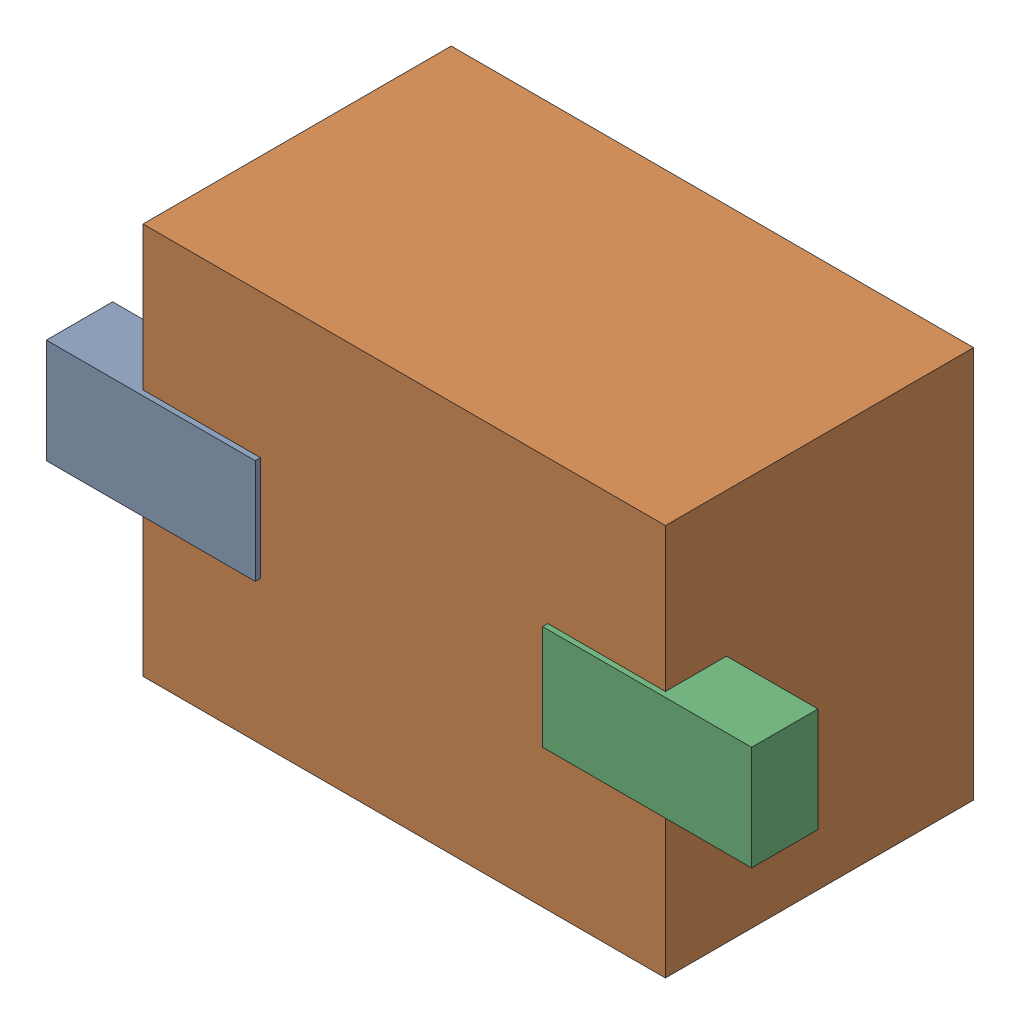
SolidWorks assembly D4, configuration Default. Lengths in mm.
Overall size (2.7 1.5 1.2).
6 component instances, 2 part files, 0 mates.
Components (placement in the parent):
- 710424080_6-1: 710424080_6 [Default] at (9.75 32.7 -0.6655) size (0.8 0.4 0.25)
  - Extruded (18)-1: Extruded (18) [Default] at origin size (0.8 0.4 0.25)
- 710423952_3-1: 710423952_3 [Default] at (10.7 32.7 -1.6115) size (2 1.5 1.18)
  - Extruded (19)-1: Extruded (19) [Default] at origin size (2 1.5 1.18)
- 710424080_7-1: 710424080_7 [Default] at (11.65 32.7 -0.6655) size (0.8 0.4 0.25)
  - Extruded (18)-1: Extruded (18) [Default] at origin size (0.8 0.4 0.25)
